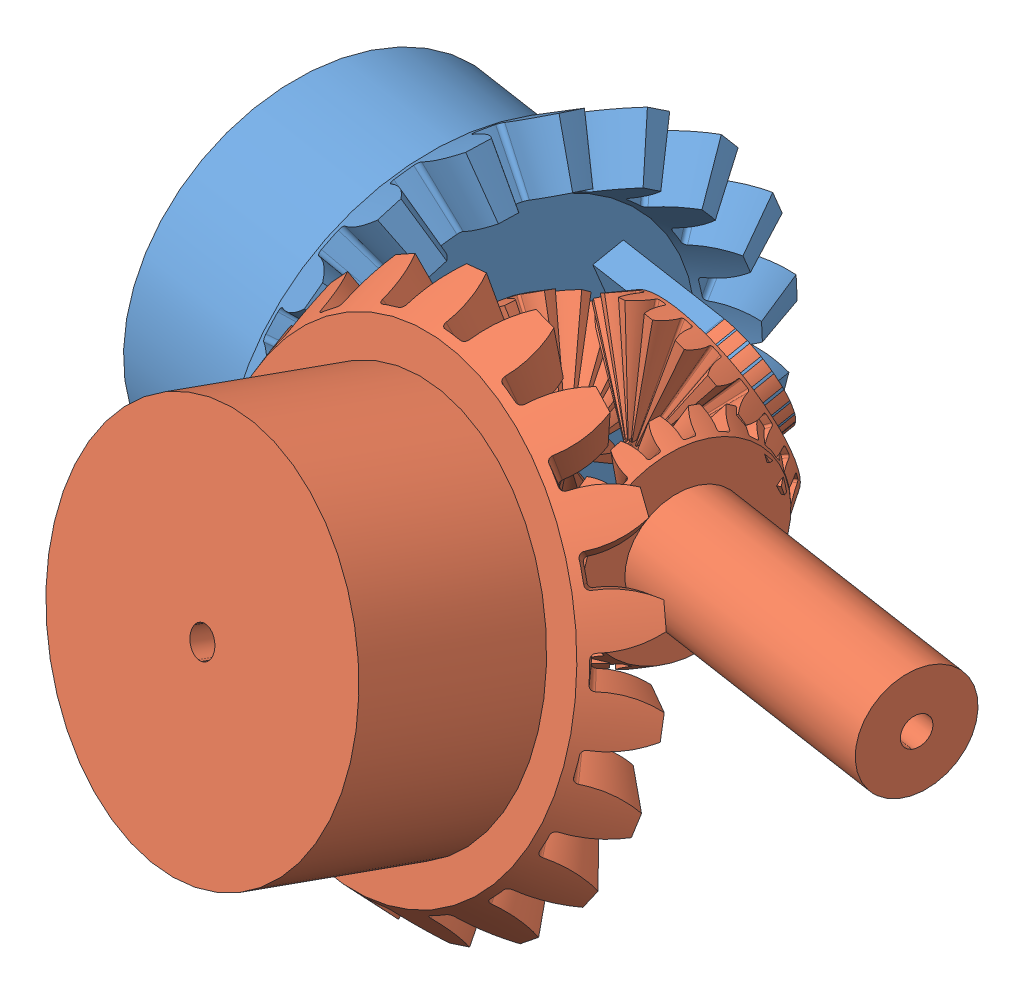
SolidWorks assembly Aries project Differential, configuration Default. Lengths in mm.
Overall size (22.74 20.21 25.25).
11 component instances, 2 part files, 17 mates.
Components (placement in the parent):
- Differential part 1-3: Differential part 1 [Default] at (6.6336 -19.3941 6.6309) x (0.98773 0.008955 0.155913) z (0.064078 -0.933684 -0.352318) size (10.65 13.87 13.91)
- Differential part 2-4: Differential part 2 [Default] at (11.5308 -21.8615 6.8199) x (0.98773 0.008955 0.155913) z (-0.120067 0.681953 0.721474) size (9.81 5.94 5.96)
  - straight bevel gear_iso-1: straight bevel gear_iso [ISO - Straight bevel gear 0.3M 19GT 12PT 14.5PA 7FW ---19O3H10MD0.8N] at (-3.5446 0.6303 2.0777) size (9.81 5.94 5.96)
- Differential part 2-5: Differential part 2 [Default] at (9.6513 -21.0712 6.6203) x (0.142419 0.357986 -0.922802) z (0.893588 0.354464 0.275419) size (9.81 5.94 5.96)
  - straight bevel gear_iso-1: straight bevel gear_iso [ISO - Straight bevel gear 0.3M 19GT 12PT 14.5PA 7FW ---19O3H10MD0.8N] at (-3.5446 0.6303 2.0777) size (9.81 5.94 5.96)
- Differential part 2-6: Differential part 2 [Default] at (13.2252 -20.4695 8.5856) x (-0.142419 -0.357986 0.922802) z (-0.968764 -0.1408 -0.204134) size (9.81 5.94 5.96)
  - straight bevel gear_iso-1: straight bevel gear_iso [ISO - Straight bevel gear 0.3M 19GT 12PT 14.5PA 7FW ---19O3H10MD0.8N] at (-3.5446 0.6303 2.0777) size (9.81 5.94 5.96)
- Differential part 2-7: Differential part 2 [Default] at (10.6434 -18.1036 6.6974) x (-0.98773 -0.008955 -0.155913) z (-0.106959 -0.688662 0.71715) size (9.81 5.94 5.96)
  - straight bevel gear_iso-1: straight bevel gear_iso [ISO - Straight bevel gear 0.3M 19GT 12PT 14.5PA 7FW ---19O3H10MD0.8N] at (-3.5446 0.6303 2.0777) size (9.81 5.94 5.96)
- Differential part 1-4: Differential part 1 [Default] at (12.2662 -18.8312 15.7512) x (0.153433 -0.241744 -0.958133) z (0.933412 -0.282803 0.220828) size (7.08 13.87 13.91)
  - straight bevel gear_iso-4: straight bevel gear_iso [ISO - Straight bevel gear 0.7M 19GT 12PT 14.5PA 1.6FW ---19O10H10MD0.8N] at (0.225 0.7054 0.4074) size (7.08 13.87 13.91)
Mates (geometry in assembly coordinates):
- Concentric4: concentric aligned: cylinder of Differential part 1-3 through (16.6588 -19.9354 8.7326) axis (-0.98773 -0.008955 -0.155913) radius 0.4; cylinder of Differential part 2-4/straight bevel gear_iso-1 through (17.7206 -19.9258 8.9002) axis (-0.98773 -0.008955 -0.155913) radius 0.4
- Coincident3: coincident anti-aligned: plane of Differential part 1-3 through (7.8433 -20.0154 7.341) normal (0.98773 0.008955 0.155913); plane of Differential part 2-4/straight bevel gear_iso-1 through (7.8433 -20.0154 7.341) normal (-0.98773 -0.008955 -0.155913)
- Perpendicular3: perpendicular: cylinder of Differential part 2-4/straight bevel gear_iso-1 through (17.1991 0.9666 2.8214) axis (-0.987608 0 -0.156939) radius 0.4; cylinder of Differential part 2-5/straight bevel gear_iso-1 through (11.4762 5.5166 -3.4744) axis (-0.119265 -0.649987 0.750528) radius 0.4
- Parallel1: parallel anti-aligned: plane of Differential part 1-3 through (17.1972 -19.5993 12.197) normal (0.142419 0.357986 -0.922802); plane of Differential part 2-5/straight bevel gear_iso-1 through (9.6332 -23.8282 17.7709) normal (-0.142419 -0.357986 0.922802)
- GearMate2: gear = 1 : 1 mm: cone of Differential part 2-5/straight bevel gear_iso-1 through (10.8272 -20.8269 10.0345) axis (-0.142419 -0.357986 0.922802); cone of Differential part 2-4/straight bevel gear_iso-1 through (8.4842 -20.0096 7.4422) axis (-0.98773 -0.008955 -0.155913)
- Coincident7: coincident anti-aligned: plane of Differential part 1-3 through (17.1972 -19.5993 12.197) normal (0.142419 0.357986 -0.922802); plane of Differential part 2-5/straight bevel gear_iso-1 through (10.7348 -21.0592 10.6333) normal (-0.142419 -0.357986 0.922802)
- Coincident8: coincident aligned: plane of Differential part 1-3 through (17.2755 -22.6867 11.8783) normal (-0.142419 -0.357986 0.922802); circle of Differential part 2-5/straight bevel gear_iso-1
- Concentric8: concentric aligned: circle of Differential part 2-5/straight bevel gear_iso-1
- Coincident10: coincident anti-aligned: plane of Differential part 1-3 through (18.0517 -17.4513 6.6602) normal (-0.142419 -0.357986 0.922802); plane of Differential part 2-6/straight bevel gear_iso-1 through (11.5893 -18.9113 5.0965) normal (0.142419 0.357986 -0.922802)
- Concentric9: concentric aligned: circle of Differential part 1-3; circle of Differential part 2-6/straight bevel gear_iso-1
- GearMate3: gear = 1 : 1 mm: cone of Differential part 2-6/straight bevel gear_iso-1 through (11.4969 -19.1436 5.6953) axis (0.142419 0.357986 -0.922802); cone of Differential part 2-4/straight bevel gear_iso-1 through (8.4842 -20.0096 7.4422) axis (-0.98773 -0.008955 -0.155913)
- Concentric10: concentric anti-aligned: cylinder of Differential part 2-4/straight bevel gear_iso-1 through (17.7206 -19.9258 8.9002) axis (-0.98773 -0.008955 -0.155913) radius 0.4; cylinder of Differential part 2-7/straight bevel gear_iso-1 through (4.1166 -20.0492 6.7528) axis (0.98773 0.008955 0.155913) radius 0.4
- GearMate4: gear = 1 : 1 mm: cone of Differential part 2-7/straight bevel gear_iso-1 through (13.353 -19.9654 8.2107) axis (0.98773 0.008955 0.155913); cone of Differential part 2-6/straight bevel gear_iso-1 through (11.4969 -19.1436 5.6953) axis (0.142419 0.357986 -0.922802)
- Coincident12: coincident aligned: circle of Differential part 1-3; cylinder of Differential part 2-5/straight bevel gear_iso-1 through (12.159 -17.4794 1.4052) axis (-0.142419 -0.357986 0.922802) radius 0.4
- Perpendicular4: perpendicular: line of Differential part 1-3 through (2.1237 -20.0672 6.4382) axis (0.98773 0.008955 0.155913); line of Differential part 1-4/straight bevel gear_iso-4 through (12.1862 -17.206 20.0152) axis (0.153433 -0.241744 -0.958133)
- GearMate5: gear = 1 : 1 mm: cone of Differential part 1-4/straight bevel gear_iso-4 through (13.1418 -18.7117 14.0477) axis (-0.153433 0.241744 0.958133); cone of Differential part 1-3 through (8.2756 -20.0114 7.4093) axis (-0.98773 -0.008955 -0.155913)
- Concentric11: concentric anti-aligned: cylinder of Differential part 1-4/straight bevel gear_iso-4 through (12.1862 -17.206 20.0152) axis (0.153433 -0.241744 -0.958133) radius 5
